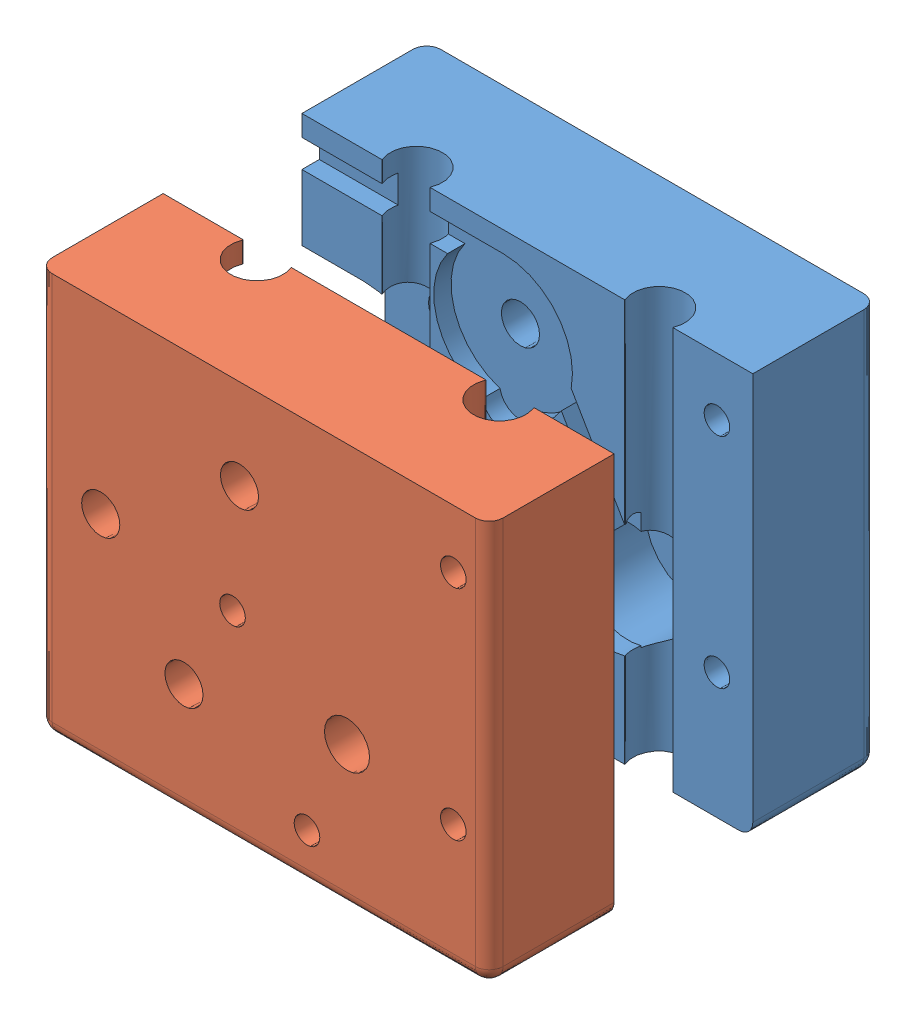
SolidWorks assembly MIRROR_MotorSupportCover2, configuration Default. Lengths in mm.
Overall size (65 58 56).
2 component instances, 2 part files, 0 mates.
Components (placement in the parent):
- MirrorMotorSupportCover-1: MirrorMotorSupportCover [Default] at (33.699 21.9668 53.0349) size (65 58 18.47)
- MirrorMirrorMotorSupportCover-2: MirrorMirrorMotorSupportCover [Default] at (33.699 21.9668 73.0349) size (65 58 18.47)
